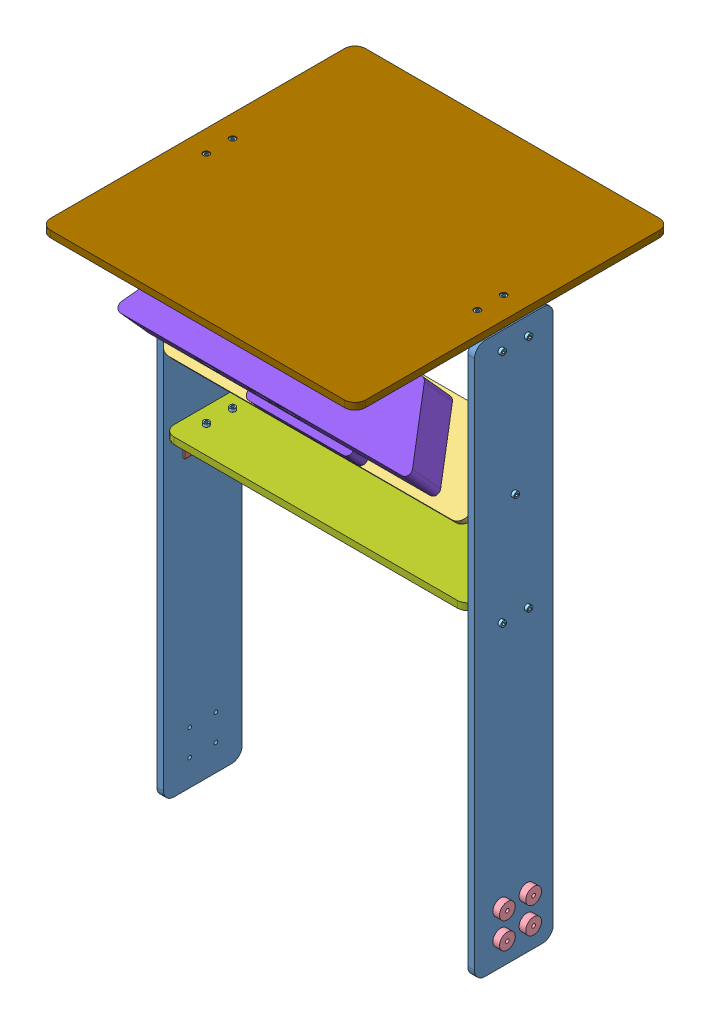
SolidWorks assembly Assembly_model_stairs_top_2, configuration Default. Lengths in mm.
Overall size (315.39 531.34 300).
66 component instances, 9 part files, 53 mates.
Components (placement in the parent):
- Part11-4: Part11 [Default] at (362.0256 34.666 386.9752) x (0 -1 0) z (0 0 1) size (525 6.35 75)
- 1556A410_BRACKET-15: 1556A410_BRACKET [1556A41] at (362.0256 168.9634 397.5977) x (-1 0 0) z (0 -0.743145 -0.669131) size (25.4 12.7 25.4)
- Part2-1: Part2 [Default] at (217.0306 168.9634 397.5977) x (1 0 0) z (0 -0.669131 0.743145) size (290 6.35 75)
- Part11-5: Part11 [Default] at (72.0356 34.666 386.9752) x (0 -1 0) z (0 0 -1) size (525 6.35 75)
- 1556A410_BRACKET-16: 1556A410_BRACKET [1556A41] at (72.0356 168.9634 397.5977) x (1 0 0) z (0 -0.743145 -0.669131) size (25.4 12.7 25.4)
- washer-17: washer [Default] at (368.3756 -202.834 399.4752) x (0 0 -1) z (0 -1 0) size (15 6.35 15)
- washer-18: washer [Default] at (368.3756 -177.834 399.4752) x (0 0 -1) z (0 -1 0) size (15 6.35 15)
- washer-19: washer [Default] at (368.3756 -202.834 374.4752) x (0 0 -1) z (0 -1 0) size (15 6.35 15)
- washer-20: washer [Default] at (368.3756 -177.834 374.4752) x (0 0 -1) z (0 -1 0) size (15 6.35 15)
- washer-21: washer [Default] at (65.6856 -202.834 399.4752) x (0 0 1) z (0 -1 0) size (15 6.35 15)
- washer-22: washer [Default] at (65.6856 -177.834 399.4752) x (0 0 1) z (0 -1 0) size (15 6.35 15)
- washer-23: washer [Default] at (65.6856 -202.834 374.4752) x (0 0 1) z (0 -1 0) size (15 6.35 15)
- washer-24: washer [Default] at (65.6856 -177.834 374.4752) x (0 0 1) z (0 -1 0) size (15 6.35 15)
- 1556A410_BRACKET-17: 1556A410_BRACKET [1556A41] at (72.0356 73.041 399.4752) x (1 0 0) z (0 -1 0) size (25.4 12.7 25.4)
- 91290A123_BLACK-OXIDE CLASS 12.9 SOCKET HEAD CAP SCREW-23: 91290A123_BLACK-OXIDE CLASS 12.9 SOCKET HEAD CAP SCREW [91290A123] at (85.6856 57.166 399.4752) x (0 0 -1) z (1 0 0) size (5.5 5.5 23.27)
- 92497A200_ZINC YELLOW-CHROMATE PLATED STEEL HEX NUT-24: 92497A200_ZINC YELLOW-CHROMATE PLATED STEEL HEX NUT [92497A200] at (75.0136 57.166 399.4752) x (0 0 -1) z (1 0 0) size (5.5 6.35 2.78)
- 1556A410_BRACKET-18: 1556A410_BRACKET [1556A41] at (72.0356 73.041 374.4752) x (1 0 0) z (0 -1 0) size (25.4 12.7 25.4)
- 91290A123_BLACK-OXIDE CLASS 12.9 SOCKET HEAD CAP SCREW-24: 91290A123_BLACK-OXIDE CLASS 12.9 SOCKET HEAD CAP SCREW [91290A123] at (85.6856 57.166 374.4752) x (0 0 -1) z (1 0 0) size (5.5 5.5 23.27)
- 92497A200_ZINC YELLOW-CHROMATE PLATED STEEL HEX NUT-25: 92497A200_ZINC YELLOW-CHROMATE PLATED STEEL HEX NUT [92497A200] at (75.0136 57.166 374.4752) x (0 0 -1) z (1 0 0) size (5.5 6.35 2.78)
- 1556A410_BRACKET-19: 1556A410_BRACKET [1556A41] at (72.0356 297.161 399.4752) x (1 0 0) z (0 -1 0) size (25.4 12.7 25.4)
- 91290A123_BLACK-OXIDE CLASS 12.9 SOCKET HEAD CAP SCREW-25: 91290A123_BLACK-OXIDE CLASS 12.9 SOCKET HEAD CAP SCREW [91290A123] at (85.6856 281.286 399.4752) x (0 0 -1) z (1 0 0) size (5.5 5.5 23.27)
- 92497A200_ZINC YELLOW-CHROMATE PLATED STEEL HEX NUT-26: 92497A200_ZINC YELLOW-CHROMATE PLATED STEEL HEX NUT [92497A200] at (75.0136 281.286 399.4752) x (0 0 -1) z (1 0 0) size (5.5 6.35 2.78)
- 1556A410_BRACKET-20: 1556A410_BRACKET [1556A41] at (72.0356 297.161 374.4752) x (1 0 0) z (0 -1 0) size (25.4 12.7 25.4)
- 91290A123_BLACK-OXIDE CLASS 12.9 SOCKET HEAD CAP SCREW-26: 91290A123_BLACK-OXIDE CLASS 12.9 SOCKET HEAD CAP SCREW [91290A123] at (85.6856 281.286 374.4752) x (0 0 -1) z (1 0 0) size (5.5 5.5 23.27)
- 92497A200_ZINC YELLOW-CHROMATE PLATED STEEL HEX NUT-27: 92497A200_ZINC YELLOW-CHROMATE PLATED STEEL HEX NUT [92497A200] at (75.0136 281.286 374.4752) x (0 0 -1) z (1 0 0) size (5.5 6.35 2.78)
- 1556A410_BRACKET-21: 1556A410_BRACKET [1556A41] at (362.0256 73.041 399.4752) x (-1 0 0) z (0 -1 0) size (25.4 12.7 25.4)
- 91290A123_BLACK-OXIDE CLASS 12.9 SOCKET HEAD CAP SCREW-27: 91290A123_BLACK-OXIDE CLASS 12.9 SOCKET HEAD CAP SCREW [91290A123] at (348.3756 57.166 399.4752) x (0 0 1) z (-1 0 0) size (5.5 5.5 23.27)
- 92497A200_ZINC YELLOW-CHROMATE PLATED STEEL HEX NUT-28: 92497A200_ZINC YELLOW-CHROMATE PLATED STEEL HEX NUT [92497A200] at (359.0476 57.166 399.4752) x (0 0 -1) z (1 0 0) size (5.5 6.35 2.78)
- 1556A410_BRACKET-22: 1556A410_BRACKET [1556A41] at (362.0256 73.041 374.4752) x (-1 0 0) z (0 -1 0) size (25.4 12.7 25.4)
- 1556A410_BRACKET-23: 1556A410_BRACKET [1556A41] at (362.0256 297.161 399.4752) x (-1 0 0) z (0 -1 0) size (25.4 12.7 25.4)
- 1556A410_BRACKET-24: 1556A410_BRACKET [1556A41] at (362.0256 297.161 374.4752) x (-1 0 0) z (0 -1 0) size (25.4 12.7 25.4)
- 91290A123_BLACK-OXIDE CLASS 12.9 SOCKET HEAD CAP SCREW-28: 91290A123_BLACK-OXIDE CLASS 12.9 SOCKET HEAD CAP SCREW [91290A123] at (348.3756 57.166 374.4752) x (0 0 1) z (-1 0 0) size (5.5 5.5 23.27)
- 91290A123_BLACK-OXIDE CLASS 12.9 SOCKET HEAD CAP SCREW-29: 91290A123_BLACK-OXIDE CLASS 12.9 SOCKET HEAD CAP SCREW [91290A123] at (348.3756 281.286 399.4752) x (0 0 1) z (-1 0 0) size (5.5 5.5 23.27)
- 91290A123_BLACK-OXIDE CLASS 12.9 SOCKET HEAD CAP SCREW-30: 91290A123_BLACK-OXIDE CLASS 12.9 SOCKET HEAD CAP SCREW [91290A123] at (348.3756 281.286 374.4752) x (0 0 1) z (-1 0 0) size (5.5 5.5 23.27)
- 92497A200_ZINC YELLOW-CHROMATE PLATED STEEL HEX NUT-29: 92497A200_ZINC YELLOW-CHROMATE PLATED STEEL HEX NUT [92497A200] at (359.0476 57.166 374.4752) x (0 0 -1) z (1 0 0) size (5.5 6.35 2.78)
- 92497A200_ZINC YELLOW-CHROMATE PLATED STEEL HEX NUT-30: 92497A200_ZINC YELLOW-CHROMATE PLATED STEEL HEX NUT [92497A200] at (359.0476 281.286 399.4752) x (0 0 -1) z (1 0 0) size (5.5 6.35 2.78)
- 92497A200_ZINC YELLOW-CHROMATE PLATED STEEL HEX NUT-31: 92497A200_ZINC YELLOW-CHROMATE PLATED STEEL HEX NUT [92497A200] at (359.0476 281.286 374.4752) x (0 0 -1) z (1 0 0) size (5.5 6.35 2.78)
- Part5-2: Part5 [Default] at (217.0306 73.041 386.9752) size (290 6.35 75)
- 91290A123_BLACK-OXIDE CLASS 12.9 SOCKET HEAD CAP SCREW-31: 91290A123_BLACK-OXIDE CLASS 12.9 SOCKET HEAD CAP SCREW [91290A123] at (87.9106 59.391 399.4752) x (1 0 0) z (0 -1 0) size (5.5 5.5 23.27)
- 92497A200_ZINC YELLOW-CHROMATE PLATED STEEL HEX NUT-33: 92497A200_ZINC YELLOW-CHROMATE PLATED STEEL HEX NUT [92497A200] at (87.9106 70.063 399.4752) x (1 0 0) z (0 -1 0) size (5.5 6.35 2.78)
- 91290A123_BLACK-OXIDE CLASS 12.9 SOCKET HEAD CAP SCREW-32: 91290A123_BLACK-OXIDE CLASS 12.9 SOCKET HEAD CAP SCREW [91290A123] at (87.9106 59.391 374.4752) x (1 0 0) z (0 -1 0) size (5.5 5.5 23.27)
- 92497A200_ZINC YELLOW-CHROMATE PLATED STEEL HEX NUT-34: 92497A200_ZINC YELLOW-CHROMATE PLATED STEEL HEX NUT [92497A200] at (87.9106 70.063 374.4752) x (1 0 0) z (0 -1 0) size (5.5 6.35 2.78)
- 91290A123_BLACK-OXIDE CLASS 12.9 SOCKET HEAD CAP SCREW-35: 91290A123_BLACK-OXIDE CLASS 12.9 SOCKET HEAD CAP SCREW [91290A123] at (87.9106 59.391 374.4752) x (1 0 0) z (0 -1 0) size (5.5 5.5 23.27)
- 91290A123_BLACK-OXIDE CLASS 12.9 SOCKET HEAD CAP SCREW-36: 91290A123_BLACK-OXIDE CLASS 12.9 SOCKET HEAD CAP SCREW [91290A123] at (346.1506 59.391 399.4752) x (1 0 0) z (0 -1 0) size (5.5 5.5 23.27)
- 91290A123_BLACK-OXIDE CLASS 12.9 SOCKET HEAD CAP SCREW-37: 91290A123_BLACK-OXIDE CLASS 12.9 SOCKET HEAD CAP SCREW [91290A123] at (346.1506 59.391 374.4752) x (1 0 0) z (0 -1 0) size (5.5 5.5 23.27)
- 92497A200_ZINC YELLOW-CHROMATE PLATED STEEL HEX NUT-37: 92497A200_ZINC YELLOW-CHROMATE PLATED STEEL HEX NUT [92497A200] at (87.9106 70.063 374.4752) x (1 0 0) z (0 -1 0) size (5.5 6.35 2.78)
- 92497A200_ZINC YELLOW-CHROMATE PLATED STEEL HEX NUT-38: 92497A200_ZINC YELLOW-CHROMATE PLATED STEEL HEX NUT [92497A200] at (346.1506 70.063 399.4752) x (1 0 0) z (0 -1 0) size (5.5 6.35 2.78)
- 92497A200_ZINC YELLOW-CHROMATE PLATED STEEL HEX NUT-39: 92497A200_ZINC YELLOW-CHROMATE PLATED STEEL HEX NUT [92497A200] at (346.1506 70.063 374.4752) x (1 0 0) z (0 -1 0) size (5.5 6.35 2.78)
- 91290A123_BLACK-OXIDE CLASS 12.9 SOCKET HEAD CAP SCREW-38: 91290A123_BLACK-OXIDE CLASS 12.9 SOCKET HEAD CAP SCREW [91290A123] at (87.9106 158.8195 388.464) x (1 0 0) z (0 -0.743145 -0.669131) size (5.5 5.5 23.27)
- 92497A200_ZINC YELLOW-CHROMATE PLATED STEEL HEX NUT-40: 92497A200_ZINC YELLOW-CHROMATE PLATED STEEL HEX NUT [92497A200] at (87.9106 166.7504 395.605) x (1 0 0) z (0 -0.743145 -0.669131) size (5.5 6.35 2.78)
- 91290A123_BLACK-OXIDE CLASS 12.9 SOCKET HEAD CAP SCREW-39: 91290A123_BLACK-OXIDE CLASS 12.9 SOCKET HEAD CAP SCREW [91290A123] at (346.1506 158.8195 388.464) x (1 0 0) z (0 -0.743145 -0.669131) size (5.5 5.5 23.27)
- 92497A200_ZINC YELLOW-CHROMATE PLATED STEEL HEX NUT-41: 92497A200_ZINC YELLOW-CHROMATE PLATED STEEL HEX NUT [92497A200] at (346.1506 166.7504 395.605) x (1 0 0) z (0 -0.743145 -0.669131) size (5.5 6.35 2.78)
- 91290A123_BLACK-OXIDE CLASS 12.9 SOCKET HEAD CAP SCREW-40: 91290A123_BLACK-OXIDE CLASS 12.9 SOCKET HEAD CAP SCREW [91290A123] at (85.6856 157.166 386.9752) x (0 0 -1) z (1 0 0) size (5.5 5.5 23.27)
- 92497A200_ZINC YELLOW-CHROMATE PLATED STEEL HEX NUT-42: 92497A200_ZINC YELLOW-CHROMATE PLATED STEEL HEX NUT [92497A200] at (75.0136 157.166 386.9752) x (0 -0.924225 -0.381849) z (-1 0 0) size (5.5 6.35 2.78)
- 91290A123_BLACK-OXIDE CLASS 12.9 SOCKET HEAD CAP SCREW-41: 91290A123_BLACK-OXIDE CLASS 12.9 SOCKET HEAD CAP SCREW [91290A123] at (348.3756 157.166 386.9752) x (0 0 1) z (-1 0 0) size (5.5 5.5 23.27)
- 92497A200_ZINC YELLOW-CHROMATE PLATED STEEL HEX NUT-43: 92497A200_ZINC YELLOW-CHROMATE PLATED STEEL HEX NUT [92497A200] at (359.0476 157.166 386.9752) x (0 1 0) z (-1 0 0) size (5.5 6.35 2.78)
- 92497A200_ZINC YELLOW-CHROMATE PLATED STEEL HEX NUT-44: 92497A200_ZINC YELLOW-CHROMATE PLATED STEEL HEX NUT [92497A200] at (346.1506 294.183 399.4752) x (1 0 0) z (0 -1 0) size (5.5 6.35 2.78)
- kinect-1: kinect [Default] at (217.0306 231.9723 389.4159) x (1 0 0) z (0 -0.669131 0.743145) size (278.26 75 75)
- Part61-1: Part61 [Default] at (217.0306 297.161 386.9752) size (300 6.35 300)
- 91290A123_BLACK-OXIDE CLASS 12.9 SOCKET HEAD CAP SCREW-44: 91290A123_BLACK-OXIDE CLASS 12.9 SOCKET HEAD CAP SCREW [91290A123] at (346.1506 280.011 399.4752) x (1 0 0) z (0 -1 0) size (5.5 5.5 23.27)
- 92497A200_ZINC YELLOW-CHROMATE PLATED STEEL HEX NUT-46: 92497A200_ZINC YELLOW-CHROMATE PLATED STEEL HEX NUT [92497A200] at (87.9106 294.183 399.4752) x (1 0 0) z (0 -1 0) size (5.5 6.35 2.78)
- 92497A200_ZINC YELLOW-CHROMATE PLATED STEEL HEX NUT-47: 92497A200_ZINC YELLOW-CHROMATE PLATED STEEL HEX NUT [92497A200] at (346.1506 294.183 374.4752) x (1 0 0) z (0 -1 0) size (5.5 6.35 2.78)
- 92497A200_ZINC YELLOW-CHROMATE PLATED STEEL HEX NUT-48: 92497A200_ZINC YELLOW-CHROMATE PLATED STEEL HEX NUT [92497A200] at (87.9106 294.183 374.4752) x (1 0 0) z (0 -1 0) size (5.5 6.35 2.78)
- 91290A123_BLACK-OXIDE CLASS 12.9 SOCKET HEAD CAP SCREW-45: 91290A123_BLACK-OXIDE CLASS 12.9 SOCKET HEAD CAP SCREW [91290A123] at (87.9106 280.011 399.4752) x (1 0 0) z (0 -1 0) size (5.5 5.5 23.27)
- 91290A123_BLACK-OXIDE CLASS 12.9 SOCKET HEAD CAP SCREW-46: 91290A123_BLACK-OXIDE CLASS 12.9 SOCKET HEAD CAP SCREW [91290A123] at (346.1506 280.011 374.4752) x (1 0 0) z (0 -1 0) size (5.5 5.5 23.27)
- 91290A123_BLACK-OXIDE CLASS 12.9 SOCKET HEAD CAP SCREW-47: 91290A123_BLACK-OXIDE CLASS 12.9 SOCKET HEAD CAP SCREW [91290A123] at (87.9106 280.011 374.4752) x (1 0 0) z (0 -1 0) size (5.5 5.5 23.27)
Mates (geometry in assembly coordinates):
- Coincident1: coincident anti-aligned: circle of Part11-4; plane of 1556A410_BRACKET-15 through (362.0256 154.3365 375.8828) normal (1 0 0)
- Concentric4: concentric aligned: circle of Part11-4; circle of 1556A410_BRACKET-15
- Coincident2: coincident anti-aligned: plane of 1556A410_BRACKET-15 through (359.3586 173.2124 392.8787) normal (0 0.743145 0.669131); plane of Part2-1 through (217.0306 168.9634 397.5977) normal (0 -0.743145 -0.669131)
- Concentric5: concentric anti-aligned: circle of 1556A410_BRACKET-15; circle of Part2-1
- Coincident3: coincident anti-aligned: plane of Part2-1 through (217.0306 168.9634 397.5977) normal (0 -0.743145 -0.669131); plane of 1556A410_BRACKET-16 through (74.7026 164.7145 402.3166) normal (0 0.743145 0.669131)
- Concentric6: concentric anti-aligned: circle of Part2-1; circle of 1556A410_BRACKET-16
- Concentric7: concentric aligned: circle of Part11-5; circle of 1556A410_BRACKET-16
- Coincident4: coincident anti-aligned: circle of Part11-5; plane of 1556A410_BRACKET-16 through (72.0356 145.8386 385.3207) normal (-1 0 0)
- Coincident5: coincident anti-aligned: circle of Part11-4; circle of washer-17
- Coincident6: coincident anti-aligned: circle of Part11-5; circle of washer-21
- Concentric8: concentric anti-aligned: circle of Part11-5; circle of 1556A410_BRACKET-17
- Coincident7: coincident aligned: circle of Part11-5; plane of 1556A410_BRACKET-17 through (72.0356 47.641 405.8252) normal (-1 0 0)
- Coincident8: coincident anti-aligned: plane of Part11-5 through (65.6856 34.666 386.9752) normal (-1 0 0); plane of 91290A123_BLACK-OXIDE CLASS 12.9 SOCKET HEAD CAP SCREW-23 through (65.6856 57.166 399.4752) normal (1 0 0)
- Concentric9: concentric anti-aligned: circle of Part11-5; circle of 91290A123_BLACK-OXIDE CLASS 12.9 SOCKET HEAD CAP SCREW-23
- Concentric10: concentric anti-aligned: circle of 1556A410_BRACKET-17; circle of 92497A200_ZINC YELLOW-CHROMATE PLATED STEEL HEX NUT-24
- Coincident11: coincident anti-aligned: plane of 1556A410_BRACKET-17 through (73.8136 47.641 405.8252) normal (1 0 0); plane of 92497A200_ZINC YELLOW-CHROMATE PLATED STEEL HEX NUT-24 through (73.8136 58.7537 402.2252) normal (-1 0 0)
- Coincident12: coincident aligned: circle of Part11-4; plane of 1556A410_BRACKET-21 through (362.0256 47.641 393.1252) normal (1 0 0)
- Concentric11: concentric anti-aligned: circle of Part11-4; circle of 1556A410_BRACKET-21
- Coincident13: coincident anti-aligned: circle of Part11-4; plane of 91290A123_BLACK-OXIDE CLASS 12.9 SOCKET HEAD CAP SCREW-27 through (368.3756 57.166 399.4752) normal (-1 0 0)
- Concentric12: concentric anti-aligned: circle of Part11-4; circle of 91290A123_BLACK-OXIDE CLASS 12.9 SOCKET HEAD CAP SCREW-27
- Concentric13: concentric aligned: circle of 1556A410_BRACKET-21; circle of 92497A200_ZINC YELLOW-CHROMATE PLATED STEEL HEX NUT-28
- Coincident14: coincident anti-aligned: circle of 1556A410_BRACKET-21; plane of 92497A200_ZINC YELLOW-CHROMATE PLATED STEEL HEX NUT-28 through (360.2476 58.7537 402.2252) normal (1 0 0)
- Concentric14: concentric anti-aligned: circle of 1556A410_BRACKET-19; circle of Part5-2
- Coincident16: coincident anti-aligned: plane of 1556A410_BRACKET-17 through (74.7026 73.041 405.8252) normal (0 1 0); plane of Part5-2 through (217.0306 73.041 386.9752) normal (0 -1 0)
- Coincident17: coincident anti-aligned: circle of Part5-2; plane of 91290A123_BLACK-OXIDE CLASS 12.9 SOCKET HEAD CAP SCREW-31 through (87.9106 79.391 399.4752) normal (0 -1 0)
- Concentric15: concentric anti-aligned: circle of Part5-2; circle of 91290A123_BLACK-OXIDE CLASS 12.9 SOCKET HEAD CAP SCREW-31
- Concentric18: concentric aligned: circle of 1556A410_BRACKET-17; circle of 92497A200_ZINC YELLOW-CHROMATE PLATED STEEL HEX NUT-33
- Coincident22: coincident anti-aligned: plane of 1556A410_BRACKET-17 through (74.7026 71.263 405.8252) normal (0 -1 0); plane of 92497A200_ZINC YELLOW-CHROMATE PLATED STEEL HEX NUT-33 through (85.1606 71.263 401.0629) normal (0 1 0)
- Coincident23: coincident anti-aligned: plane of Part2-1 through (217.0306 173.6824 401.8466) normal (0 0.743145 0.669131); plane of 91290A123_BLACK-OXIDE CLASS 12.9 SOCKET HEAD CAP SCREW-38 through (87.9106 173.6824 401.8466) normal (0 -0.743145 -0.669131)
- Concentric19: concentric anti-aligned: circle of Part2-1; circle of 91290A123_BLACK-OXIDE CLASS 12.9 SOCKET HEAD CAP SCREW-38
- Coincident24: coincident anti-aligned: plane of 1556A410_BRACKET-16 through (74.7026 163.3932 401.1269) normal (0 -0.743145 -0.669131); plane of 92497A200_ZINC YELLOW-CHROMATE PLATED STEEL HEX NUT-40 through (85.1606 166.5797 397.5878) normal (0 0.743145 0.669131)
- Concentric20: concentric anti-aligned: circle of 1556A410_BRACKET-16; circle of 92497A200_ZINC YELLOW-CHROMATE PLATED STEEL HEX NUT-40
- Coincident25: coincident anti-aligned: plane of Part11-5 through (65.6856 34.666 386.9752) normal (-1 0 0); plane of 91290A123_BLACK-OXIDE CLASS 12.9 SOCKET HEAD CAP SCREW-40 through (65.6856 157.166 386.9752) normal (1 0 0)
- Concentric21: concentric aligned: circle of Part11-5; circle of 91290A123_BLACK-OXIDE CLASS 12.9 SOCKET HEAD CAP SCREW-40
- Coincident26: coincident anti-aligned: circle of 1556A410_BRACKET-16; plane of 92497A200_ZINC YELLOW-CHROMATE PLATED STEEL HEX NUT-42 through (73.8136 159.1014 389.4927) normal (-1 0 0)
- Concentric22: concentric anti-aligned: circle of 1556A410_BRACKET-16; circle of 92497A200_ZINC YELLOW-CHROMATE PLATED STEEL HEX NUT-42
- Coincident27: coincident anti-aligned: plane of Part11-4 through (368.3756 34.666 386.9752) normal (1 0 0); plane of 91290A123_BLACK-OXIDE CLASS 12.9 SOCKET HEAD CAP SCREW-41 through (368.3756 157.166 386.9752) normal (-1 0 0)
- Concentric23: concentric aligned: circle of Part11-4; circle of 91290A123_BLACK-OXIDE CLASS 12.9 SOCKET HEAD CAP SCREW-41
- Concentric24: concentric anti-aligned: circle of 1556A410_BRACKET-15; circle of 92497A200_ZINC YELLOW-CHROMATE PLATED STEEL HEX NUT-43
- Coincident28: coincident anti-aligned: plane of 1556A410_BRACKET-15 through (360.2476 154.3365 375.8828) normal (-1 0 0); plane of 92497A200_ZINC YELLOW-CHROMATE PLATED STEEL HEX NUT-43 through (360.2476 154.416 385.3875) normal (1 0 0)
- Concentric25: concentric anti-aligned: circle of 1556A410_BRACKET-23; circle of Part61-1
- Coincident29: coincident anti-aligned: plane of 1556A410_BRACKET-23 through (359.3586 297.161 393.1252) normal (0 1 0); plane of Part61-1 through (217.0306 297.161 386.9752) normal (0 -1 0)
- Coincident30: coincident anti-aligned: plane of Part61-1 through (217.0306 303.511 386.9752) normal (0 1 0); plane of ? through (346.1506 303.511 399.4752) normal (0 -1 0)
- Concentric26: concentric anti-aligned: circle of Part61-1; circle of ?
- Coincident31: coincident anti-aligned: plane of 1556A410_BRACKET-23 through (359.3586 295.383 393.1252) normal (0 -1 0); plane of 92497A200_ZINC YELLOW-CHROMATE PLATED STEEL HEX NUT-44 through (343.4006 295.383 401.0629) normal (0 1 0)
- Concentric27: concentric aligned: circle of 1556A410_BRACKET-23; circle of 92497A200_ZINC YELLOW-CHROMATE PLATED STEEL HEX NUT-44
- Coincident32: coincident anti-aligned: line of Part2-1 through (82.0306 148.59 429.7146) axis (1 0 0); line of kinect-1 through (262.0306 148.59 429.7146) axis (-1 0 0)
- Coincident33: coincident anti-aligned: plane of Part2-1 through (217.0306 173.6824 401.8466) normal (0 0.743145 0.669131); plane of kinect-1 through (217.0306 205.9622 365.9963) normal (0 -0.743145 -0.669131)
- Distance1: distance = 95 mm: line of kinect-1 through (267.0306 195.4292 377.6944) axis (0 -0.669131 0.743145); line of Part2-1 through (362.0306 155.2813 422.2831) axis (0 0.669131 -0.743145)
- Concentric28: concentric anti-aligned: circle of 1556A410_BRACKET-24; circle of Part61-1
- Coincident34: coincident anti-aligned: plane of 1556A410_BRACKET-24 through (359.3586 297.161 368.1252) normal (0 1 0); plane of Part61-1 through (217.0306 297.161 386.9752) normal (0 -1 0)
- Coincident36: coincident anti-aligned: plane of Part61-1 through (346.1506 300.011 399.4752) normal (0 1 0); plane of 91290A123_BLACK-OXIDE CLASS 12.9 SOCKET HEAD CAP SCREW-44 through (346.1506 300.011 399.4752) normal (0 -1 0)
- Concentric29: concentric aligned: circle of Part61-1; circle of 91290A123_BLACK-OXIDE CLASS 12.9 SOCKET HEAD CAP SCREW-44
